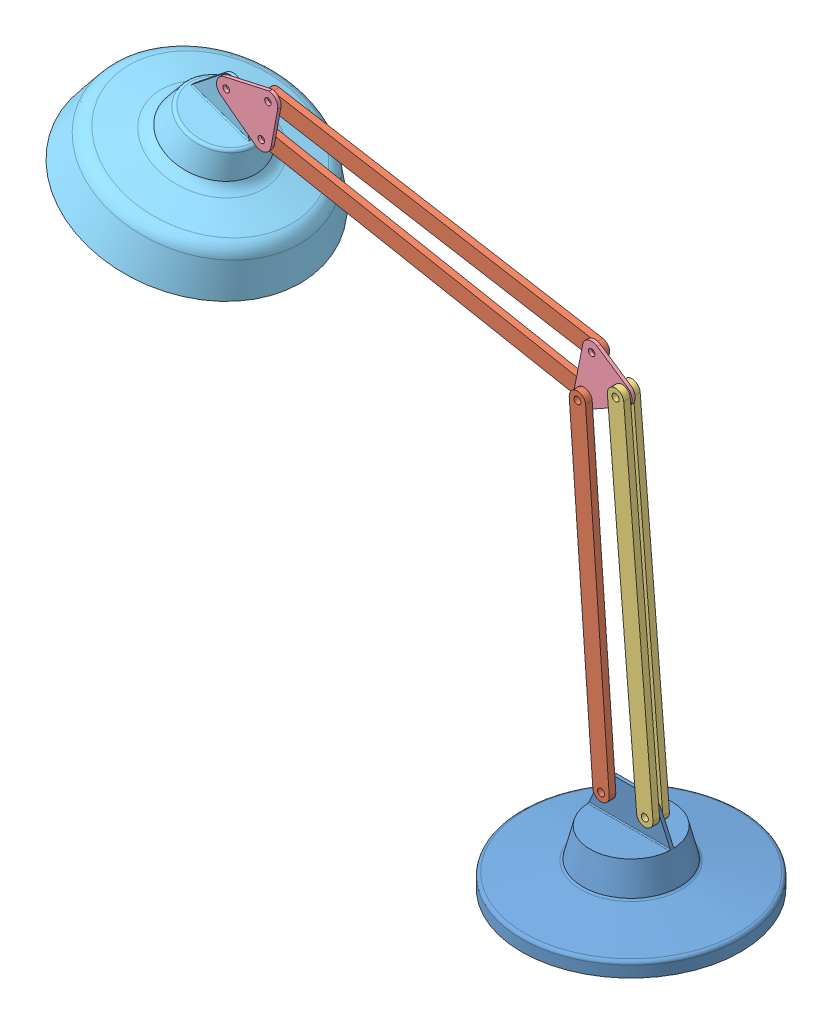
SolidWorks assembly bureaulamp, configuration Default. Lengths in mm.
Overall size (594.45 491.27 203).
9 component instances, 5 part files, 23 mates.
Components (placement in the parent):
- voet steun-1: voet steun [Default] at (92.5228 44.7612 156.3918) size (200 83 200)
- strip_kort-1: strip_kort [Default] at (61.7266 264.3722 157.8918) x (0.071975 -0.997406 0) z (0 0 1) size (315 15 6)
- strip_lang-1: strip_lang [Default] at (99.1448 274.2009 157.8918) x (0.083613 -0.996498 0) z (0 0 1) size (335 15 6)
- strip_lang-2: strip_lang [Default] at (99.1448 274.2009 148.8918) x (-0.083613 0.996498 0) z (0 0 1) size (335 15 6)
- driehoek-1: driehoek [Default] at (57.96 452.3964 157.8918) x (-0.870912 -0.491438 0) z (0 0 -1) size (58 47.99 3)
- strip_kort-2: strip_kort [Default] at (-89.8903 477.7005 148.8918) x (0.985669 -0.168694 0) z (0 0 1) size (315 15 6)
- strip_kort-3: strip_kort [Default] at (-96.4303 441.9984 148.8918) x (0.982404 -0.186769 0) z (0 0 1) size (315 15 6)
- driehoek-2: driehoek [Default] at (-237.7406 503.0046 157.8918) x (-0.799085 0.601218 0) z (0 0 -1) size (58 47.99 3)
- lampen kap-1: lampen kap [Default] at (-307.3419 402.0354 153.3918) x (0.945834 -0.324651 0) z (0 0 1) size (200 107.34 200)
Mates (geometry in assembly coordinates):
- Concentric1: concentric anti-aligned: cylinder of voet steun-1 through (72.5228 114.7612 157.8918) axis (0 0 -1) radius 3; cylinder of strip_kort-1 through (72.5228 114.7612 157.8918) axis (0 0 1) radius 3.25
- Coincident1: coincident anti-aligned: plane of voet steun-1 through (92.5228 44.7612 157.8918) normal (0 0 1); plane of strip_kort-1 through (50.9303 413.9831 157.8918) normal (0 0 -1)
- Concentric2: concentric anti-aligned: cylinder of voet steun-1 through (112.5228 114.7612 157.8918) axis (0 0 -1) radius 3; cylinder of strip_lang-1 through (112.5228 114.7612 157.8918) axis (0 0 1) radius 3.25
- Coincident2: coincident anti-aligned: plane of voet steun-1 through (92.5228 44.7612 157.8918) normal (0 0 1); plane of strip_lang-1 through (85.7668 433.6407 157.8918) normal (0 0 -1)
- Concentric3: concentric anti-aligned: cylinder of voet steun-1 through (112.5228 114.7612 157.8918) axis (0 0 -1) radius 3; cylinder of strip_lang-2 through (112.5228 114.7612 148.8918) axis (0 0 1) radius 3.25
- Coincident3: coincident anti-aligned: plane of voet steun-1 through (92.5228 44.7612 154.8918) normal (0 0 -1); plane of strip_lang-2 through (112.5228 114.7612 154.8918) normal (0 0 1)
- Concentric4: concentric aligned: cylinder of strip_kort-1 through (50.9303 413.9831 157.8918) axis (0 0 1) radius 3.25; cylinder of driehoek-1 through (50.9303 413.9831 154.8918) axis (0 0 1) radius 3
- Coincident4: coincident anti-aligned: plane of strip_kort-1 through (50.9303 413.9831 157.8918) normal (0 0 -1); plane of driehoek-1 through (50.9303 413.9831 157.8918) normal (0 0 1)
- Concentric5: concentric aligned: cylinder of strip_lang-1 through (85.7668 433.6407 157.8918) axis (0 0 1) radius 3.25; cylinder of driehoek-1 through (85.7668 433.6407 154.8918) axis (0 0 1) radius 3
- Concentric6: concentric aligned: cylinder of strip_lang-2 through (85.7668 433.6407 148.8918) axis (0 0 1) radius 3.25; cylinder of driehoek-1 through (85.7668 433.6407 154.8918) axis (0 0 1) radius 3
- Coincident5: coincident anti-aligned: plane of strip_lang-2 through (112.5228 114.7612 154.8918) normal (0 0 1); plane of driehoek-1 through (50.9303 413.9831 154.8918) normal (0 0 -1)
- Coincident7: coincident anti-aligned: plane of strip_lang-1 through (85.7668 433.6407 157.8918) normal (0 0 -1); plane of driehoek-1 through (50.9303 413.9831 157.8918) normal (0 0 1)
- Coincident8: coincident anti-aligned: plane of strip_lang-2 through (112.5228 114.7612 154.8918) normal (0 0 1); plane of driehoek-1 through (50.9303 413.9831 154.8918) normal (0 0 -1)
- Concentric7: concentric aligned: cylinder of driehoek-1 through (57.96 452.3964 154.8918) axis (0 0 1) radius 3; cylinder of strip_kort-2 through (57.96 452.3964 148.8918) axis (0 0 1) radius 3.25
- Coincident9: coincident anti-aligned: plane of driehoek-1 through (50.9303 413.9831 154.8918) normal (0 0 -1); plane of strip_kort-2 through (-237.7406 503.0046 154.8918) normal (0 0 1)
- Concentric8: concentric aligned: cylinder of driehoek-1 through (50.9303 413.9831 154.8918) axis (0 0 1) radius 3; cylinder of strip_kort-3 through (50.9303 413.9831 148.8918) axis (0 0 1) radius 3.25
- Coincident10: coincident anti-aligned: plane of driehoek-1 through (50.9303 413.9831 154.8918) normal (0 0 -1); plane of strip_kort-3 through (-243.7909 470.0137 154.8918) normal (0 0 1)
- Concentric9: concentric aligned: cylinder of strip_kort-2 through (-237.7406 503.0046 148.8918) axis (0 0 1) radius 3.25; cylinder of driehoek-2 through (-237.7406 503.0046 154.8918) axis (0 0 1) radius 3
- Concentric10: concentric aligned: cylinder of strip_kort-3 through (-243.7909 470.0137 148.8918) axis (0 0 1) radius 3.25; cylinder of driehoek-2 through (-243.7909 470.0137 154.8918) axis (0 0 1) radius 3
- Coincident11: coincident anti-aligned: plane of strip_kort-2 through (-237.7406 503.0046 154.8918) normal (0 0 1); plane of driehoek-2 through (-275.7543 494.0625 154.8918) normal (0 0 -1)
- Coincident12: coincident anti-aligned: plane of strip_kort-3 through (-243.7909 470.0137 154.8918) normal (0 0 1); plane of driehoek-2 through (-275.7543 494.0625 154.8918) normal (0 0 -1)
- Concentric11: concentric anti-aligned: cylinder of driehoek-2 through (-275.7543 494.0625 154.8918) axis (0 0 1) radius 3; cylinder of lampen kap-1 through (-275.7543 494.0625 154.8918) axis (0 0 -1) radius 3
- Coincident13: coincident anti-aligned: plane of driehoek-2 through (-275.7543 494.0625 154.8918) normal (0 0 -1); plane of lampen kap-1 through (-307.3419 402.0354 154.8918) normal (0 0 1)
